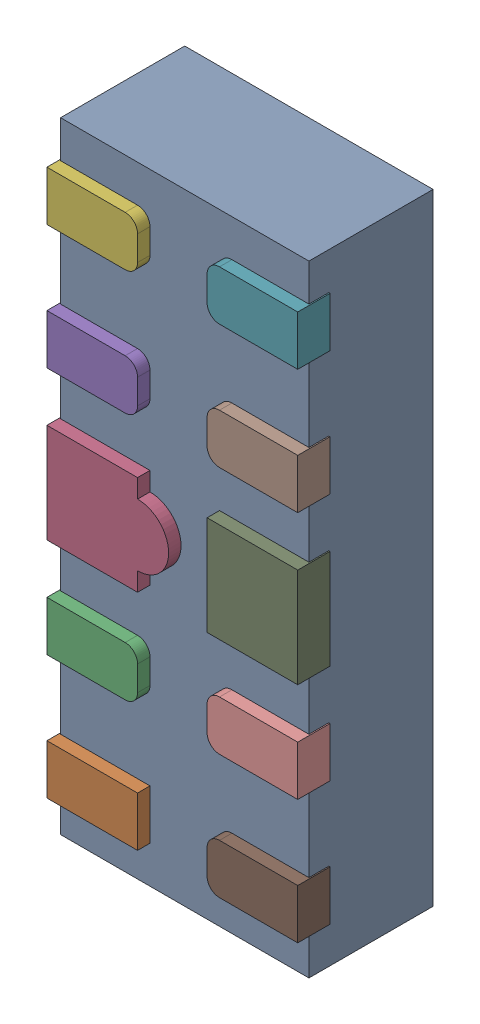
SolidWorks assembly D24, configuration Défaut. Lengths in mm.
Overall size (1.01 2.5 0.55).
12 component instances, 5 part files, 0 mates.
Components (placement in the parent):
- UDFN10-1: UDFN10 [Défaut] at (77.4135 -24.4212 -1.1719) x (0 1 0) z (-1 0 0) size (2.5 0.55 1.01)
  - User Library-UDFN10_Body-1: User Library-UDFN10_Body [Défaut] at (1.0785 0.9721 1.8983) size (2.5 0.5 1)
  - User Library-UDFN10_Pin1-1: User Library-UDFN10_Pin1 [Défaut] at (0.0785 1.0521 2.2208) x (0 0 -1) z (-1 0 0) size (0.37 0.13 0.2)
  - User Library-UDFN10_Pin2-1: User Library-UDFN10_Pin2 [Défaut] at (0.5785 1.0521 2.2208) x (0 0 1) z (1 0 0) size (0.37 0.13 0.2)
  - User Library-UDFN10_Pin4-1: User Library-UDFN10_Pin4 [Défaut] at (1.0785 0.9221 2.2208) x (0 0 1) z (-1 0 0) size (0.49 0.13 0.4)
  - User Library-UDFN10_Pin2-2: User Library-UDFN10_Pin2 [Défaut] at (1.5785 0.9221 2.2208) x (0 0 1) z (-1 0 0) size (0.37 0.13 0.2)
  - User Library-UDFN10_Pin2-3: User Library-UDFN10_Pin2 [Défaut] at (2.0785 0.9221 2.2208) x (0 0 1) z (-1 0 0) size (0.37 0.13 0.2)
  - User Library-UDFN10_Pin2-4: User Library-UDFN10_Pin2 [Défaut] at (2.0785 0.9221 1.5758) x (0 0 -1) z (1 0 0) size (0.37 0.13 0.2)
  - User Library-UDFN10_Pin2-5: User Library-UDFN10_Pin2 [Défaut] at (1.5785 0.9221 1.5758) x (0 0 -1) z (1 0 0) size (0.37 0.13 0.2)
  - User Library-UDFN10_Pin3-1: User Library-UDFN10_Pin3 [Défaut] at (1.0785 0.9221 1.5758) x (0 0 1) z (-1 0 0) size (0.37 0.13 0.4)
  - User Library-UDFN10_Pin2-6: User Library-UDFN10_Pin2 [Défaut] at (0.5785 0.9221 1.5758) x (0 0 -1) z (1 0 0) size (0.37 0.13 0.2)
  - User Library-UDFN10_Pin2-7: User Library-UDFN10_Pin2 [Défaut] at (0.0785 0.9221 1.5758) x (0 0 -1) z (1 0 0) size (0.37 0.13 0.2)
